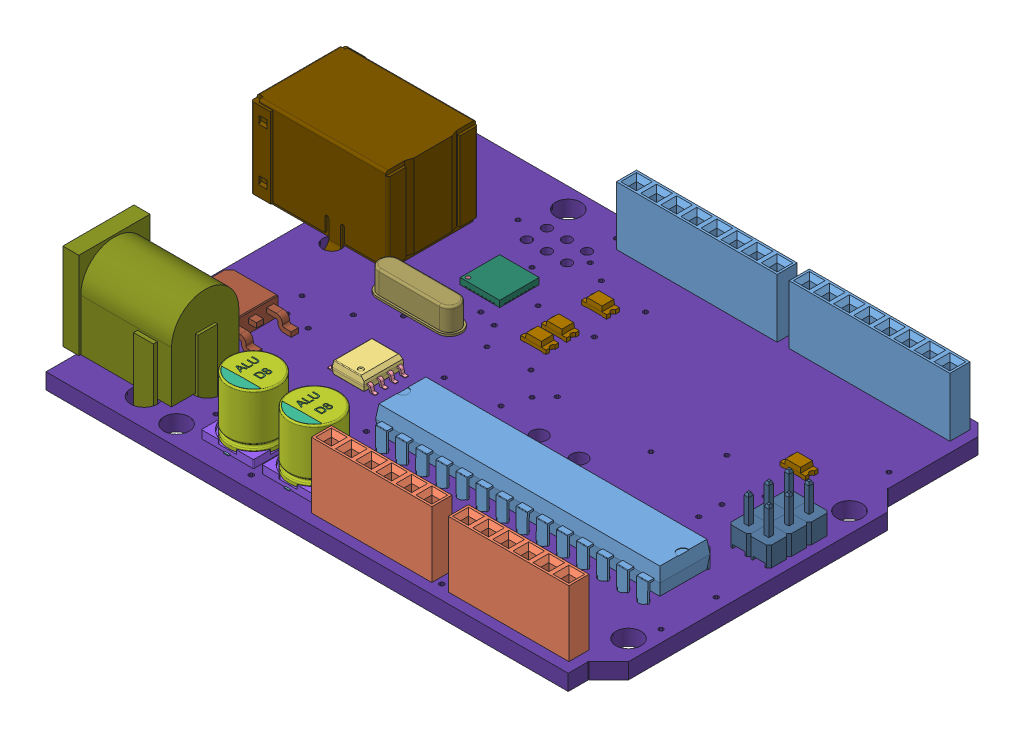
SolidWorks assembly Final, configuration Predeterminado. Lengths in mm.
Overall size (74.75 15.48 53.34).
32 component instances, 19 part files, 0 mates.
Components (placement in the parent):
- Stackable Female Pin Header_Default-1: Stackable Female Pin Header_Default [Predeterminado] at (23.9415 1.1201 -50.7298) size (20.32 8.3 2.54)
- Stackable Female Pin Header_6 Way-1: Stackable Female Pin Header_6 Way [Predeterminado] at (33.5006 2 -2.5872) size (15.24 8.3 2.54)
- User Library-SOIC-8_Default-1: User Library-SOIC-8_Default [Predeterminado] at (20.4108 1.85 -20.3024) x (0 0 -1) z (1 0 0) size (5 1.75 6.01)
  - User Library-SOIC-8_SOIC-8_Body_1_Default-1: User Library-SOIC-8_SOIC-8_Body_1_Default [Predeterminado] at origin size (5 1.6 4)
  - User Library-SOIC-8_SOIC-8_Pins_1_Default-1: User Library-SOIC-8_SOIC-8_Pins_1_Default [Predeterminado] at origin size (4.23 0.99 6.01)
- User Library-ALU-D8_Default-1: User Library-ALU-D8_Default [Predeterminado] at (28.1214 1.8 -5.7935) x (0 0 -1) z (0 1 0) size (7 6.6 7.7)
  - User Library-ALU-D8_Pins_1_Default-1: User Library-ALU-D8_Pins_1_Default [Predeterminado] at origin size (7 0.65 0.4)
  - User Library-ALU-D8_Beschriftung_1_Default-1: User Library-ALU-D8_Beschriftung_1_Default [Predeterminado] at origin size (4.35 4.98 0.11)
  - User Library-ALU-D8_K_X_F6rper_1_Default-1: User Library-ALU-D8_K_X_F6rper_1_Default [Predeterminado] at origin size (6.3 6.3 7)
  - User Library-ALU-D8_Fuss_1_Default-1: User Library-ALU-D8_Fuss_1_Default [Predeterminado] at origin size (6.6 6.6 1)
- User Library-ALU-D8_Default-2: User Library-ALU-D8_Default [Predeterminado] at (20.4464 1.8 -5.7935) x (0 0 -1) z (0 1 0) size (7 6.6 7.7)
  - User Library-ALU-D8_Pins_1_Default-1: User Library-ALU-D8_Pins_1_Default [Predeterminado] at origin size (7 0.65 0.4)
  - User Library-ALU-D8_Beschriftung_1_Default-1: User Library-ALU-D8_Beschriftung_1_Default [Predeterminado] at origin size (4.35 4.98 0.11)
  - User Library-ALU-D8_K_X_F6rper_1_Default-1: User Library-ALU-D8_K_X_F6rper_1_Default [Predeterminado] at origin size (6.3 6.3 7)
  - User Library-ALU-D8_Fuss_1_Default-1: User Library-ALU-D8_Fuss_1_Default [Predeterminado] at origin size (6.6 6.6 1)
- Stackable Female Pin Header_Default-2: Stackable Female Pin Header_Default [Predeterminado] at (45.7158 1.1368 -50.806) size (20.32 8.3 2.54)
- LED 1206_Default-1: LED 1206_Default [Predeterminado] at (28.1068 2 -36.9237) x (0 0 -1) z (1 0 0) size (1.6 1.1 3.2)
- LED 1206_Default-2: LED 1206_Default [Predeterminado] at (58.3346 2 -36.8813) x (0 0 -1) z (1 0 0) size (1.6 1.1 3.2)
- Header Vertical 2.54mm Pitch2_Header 6 Way-1: Header Vertical 2.54mm Pitch2_Header 6 Way [Predeterminado] at (62.2731 2 -29.1415) size (5.08 8.88 7.62)
- SO 369A_Standard-1: SO 369A_Standard [Predeterminado] at (5.5398 2 -17.4191) x (0 0 -1) z (0 1 0) size (6.6 10.1 2.4)
- Stackable Female Pin Header_6 Way-2: Stackable Female Pin Header_6 Way [Predeterminado] at (50.8347 2 -2.5872) size (15.24 8.3 2.54)
- XTAL Small_Default-1: XTAL Small_Default [Predeterminado] at (14.2222 2 -30.4346) x (1 0 0) z (0 1 0) size (10.67 3.05 5.63)
- LED 1206_Default-3: LED 1206_Default [Predeterminado] at (28.1068 2 -41.994) x (0 0 -1) z (1 0 0) size (1.6 1.1 3.2)
- User Library-QFN32 (FTDI)_Default-1: User Library-QFN32 (FTDI)_Default [Predeterminado] at (19.2089 2.05 -38.1588) x (-1 0 0) z (0 1 0) size (5 5 0.81)
  - User Library-QFN32 (FTDI)_Beschriftung_1_Default-1: User Library-QFN32 (FTDI)_Beschriftung_1_Default [Predeterminado] at origin size (0.51 0.51 0.05)
  - User Library-QFN32 (FTDI)_Anschl_X_FCsse_1_Default-1: User Library-QFN32 (FTDI)_Anschl_X_FCsse_1_Default [Predeterminado] x (0 -1 0) z (0 0 1) size (3.86 0.12 0.12)
  - User Library-QFN32 (FTDI)_K_X_F6rper_1_Default-1: User Library-QFN32 (FTDI)_K_X_F6rper_1_Default [Predeterminado] at origin size (5 5 0.8)
- User Library-dc range - dc connector[4840_2201]_Default-1: User Library-dc range - dc connector[4840_2201]_Default [Predeterminado] at (11.794 2 -12.8354) x (0 0 1) z (-1 0 0) size (9.51 14.5 13.83)
- PCB_Final_Default-1: PCB_Final_Default [Predeterminado] at origin size (68.58 2 53.34)
- LED 1206_Default-4: LED 1206_Default [Predeterminado] at (28.142 2 -34.2868) x (0 0 -1) z (1 0 0) size (1.6 1.1 3.2)
- User Library-67068-0000-molex_Default-1: User Library-67068-0000-molex_Default [Predeterminado] at (-6.1546 2 -38.0545) x (0.002421 0 0.999997) z (-0.999997 0 0.002421) size (15.13 15.48 17)
- IC DIP 28_Default-1: IC DIP 28_Default [Predeterminado] at (51.4233 4.3498 -16.4837) x (0 0.005002 0.999987) z (-1 0 0) size (7.87 6.22 35.94)
